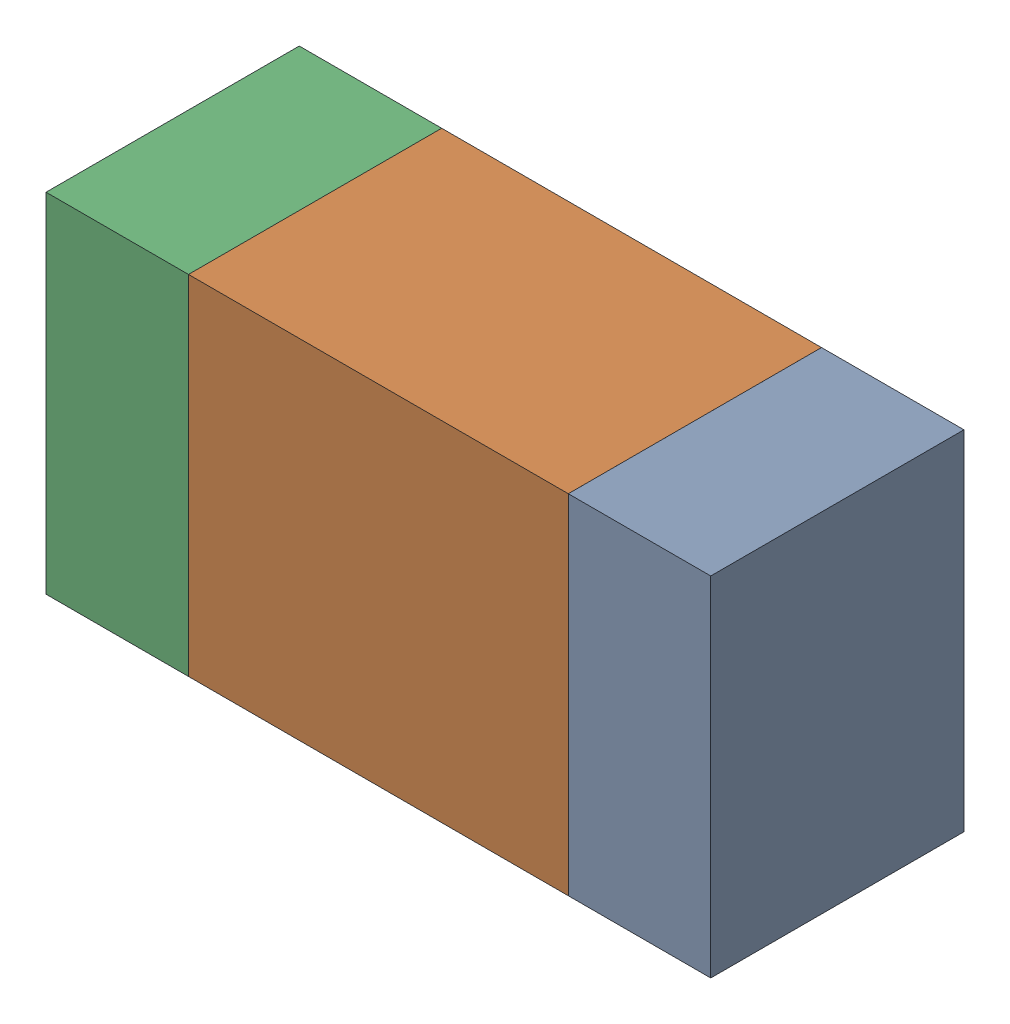
SolidWorks assembly R304_2PCB, configuration Default. Lengths in mm.
Overall size (1.05 0.55 0.4).
6 component instances, 2 part files, 0 mates.
Components (placement in the parent):
- 854785432-1: 854785432 [Default] at (141.0124 102.1999 0) size (0.22 0.55 0.4)
  - Extruded-1: Extruded [Default] at origin size (0.22 0.55 0.4)
- 854785568-1: 854785568 [Default] at (140.5999 102.1999 0) size (0.6 0.55 0.4)
  - Extruded_2-1: Extruded_2 [Default] at origin size (0.6 0.55 0.4)
- 854785432-2: 854785432 [Default] at (140.1874 102.1999 0) size (0.22 0.55 0.4)
  - Extruded-1: Extruded [Default] at origin size (0.22 0.55 0.4)
